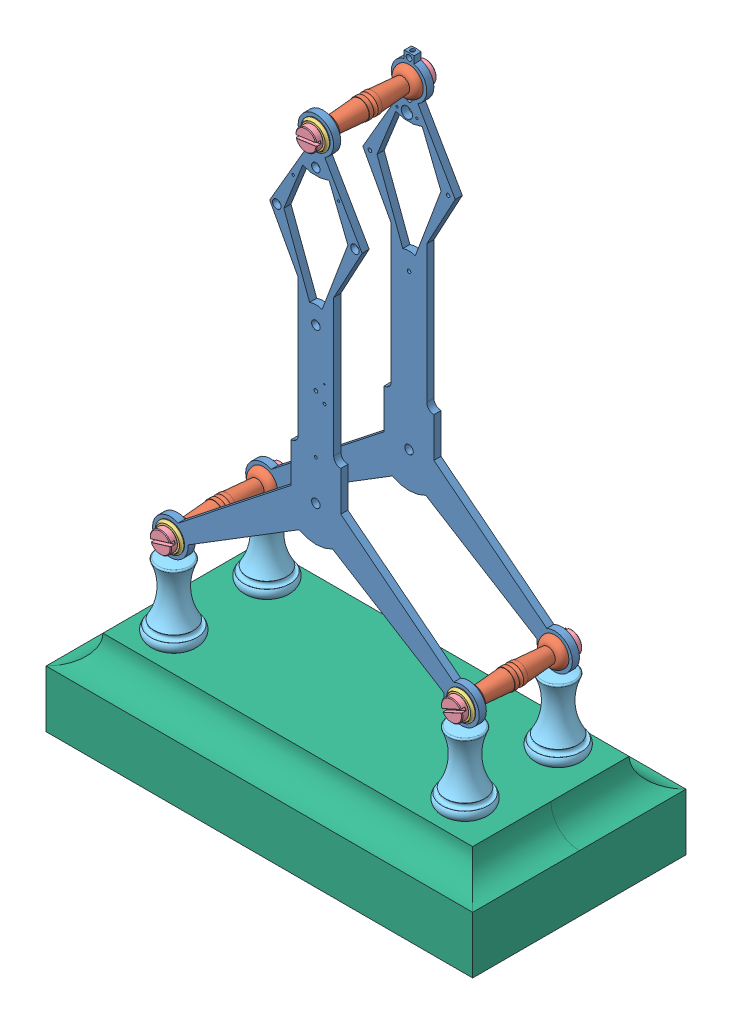
SolidWorks assembly frame assy, configuration Default. Lengths in mm.
Overall size (300 436.05 150).
22 component instances, 6 part files, 44 mates.
Components (placement in the parent):
- Frame-1: Frame [Front] at origin size (229.79 321.19 5)
- pillar-1: pillar [Default] at (0 115.9979 0) size (20 20 70.93)
- pillar-2: pillar [Default] at (102.394 -180.1971 0) x (0.987351 0.158553 0) z (0 0 1) size (20 20 70.93)
- pillar-3: pillar [Default] at (-102.394 -180.1971 0) x (0.959125 0.282984 0) z (0 0 1) size (20 20 70.93)
- Frame-2: Frame [Back] at (0 0 -60.5) x (-1 0 0) z (0 0 -1) size (229.79 326.05 5)
- washer-1: washer [Default] at (0 115.9979 7) x (0.258664 -0.965967 0) z (0 0 -1) size (20 20 2)
- frame screw-1: frame screw [Default] at (0 115.9979 7) x (-0.137342 0.990524 0) z (0.990524 0.137342 0) size (15 20 15)
- frame screw-2: frame screw [Default] at (-102.394 -180.1971 7) x (-0.292655 0.956218 0) z (0.956218 0.292655 0) size (15 20 15)
- washer-2: washer [Default] at (-102.394 -180.1971 7) x (0.408549 -0.912737 0) z (0 0 -1) size (20 20 2)
- frame screw-4: frame screw [Default] at (102.394 -180.1971 7) x (0.41203 -0.91117 0) z (-0.91117 -0.41203 0) size (15 20 15)
- washer-4: washer [Default] at (102.394 -180.1971 7) x (-0.521444 0.853286 0) z (0 0 -1) size (20 20 2)
- frame screw-6: frame screw [Default] at (102.394 -180.1971 -67.5) x (0.92649 0.37632 0) z (-0.37632 0.92649 0) size (15 20 15)
- washer-6: washer [Default] at (102.394 -180.1971 -67.5) x (-0.965884 -0.258974 0) z (0 0 1) size (20 20 2)
- frame screw-8: frame screw [Default] at (-102.394 -180.1971 -67.5) x (-0.887501 -0.460806 0) z (0.460806 -0.887501 0) size (15 20 15)
- washer-8: washer [Default] at (-102.394 -180.1971 -67.5) x (-0.90624 -0.422764 0) z (0 0 1) size (20 20 2)
- frame screw-10: frame screw [Default] at (0 115.9979 -67.5) x (0.741906 0.670504 0) z (-0.670504 0.741906 0) size (15 20 15)
- washer-10: washer [Default] at (0 115.9979 -67.5) x (-0.81906 -0.573708 0) z (0 0 1) size (20 20 2)
- foot-1: foot [Default] at (-102.394 -242.6971 2.5) x (0.145571 0 -0.989348) z (0.989348 0 0.145571) size (34 49.97 34)
- foot-2: foot [Default] at (102.394 -242.6971 2.5) x (-0.043484 0 -0.999054) z (0.999054 0 -0.043484) size (34 49.97 34)
- foot-3: foot [Default] at (102.394 -242.6971 -63) x (-0.257831 0 -0.96619) z (0.96619 0 -0.257831) size (34 49.97 34)
- foot-4: foot [Default] at (-102.394 -242.6971 -63) x (-0.477152 0 -0.878821) z (0.878821 0 -0.477152) size (34 49.97 34)
- base-1: base [Default] at (0 -302.6971 -30.25) size (300 60 150)
Mates (geometry in assembly coordinates):
- Coincident6: coincident: plane of Frame-1 through (0 0 0) normal (0 0 -1); plane of pillar-1 through (0 106.9979 0) normal (0 0 1)
- Concentric7: concentric: circle of Frame-1; circle of pillar-1
- Coincident8: coincident: plane of Frame-1 through (0 0 0) normal (0 0 -1); plane of pillar-2 through (103.821 -189.0832 0) normal (0 0 1)
- Concentric8: concentric: circle of Frame-1; circle of pillar-2
- Coincident9: coincident: plane of Frame-1 through (0 0 0) normal (0 0 -1); plane of pillar-3 through (-99.8472 -188.8292 0) normal (0 0 1)
- Concentric9: concentric: circle of Frame-1; circle of pillar-3
- Concentric17: concentric: cylinder of Frame-1 through (-102.394 -180.1971 5) axis (0 0 -1) radius 12.5; cylinder of Frame-2 through (-102.394 -180.1971 -65.5) axis (0 0 1) radius 12.5
- Coincident14: coincident: plane of Frame-1 through (0 0 5) normal (0 0 1); plane of washer-1 through (0 115.9979 5) normal (0 0 -1)
- Concentric18: concentric: circle of Frame-1; circle of washer-1
- Coincident13: coincident: plane of pillar-1 through (0 106.9979 -60.5) normal (0 0 -1); plane of Frame-2 through (0 0 -60.5) normal (0 0 1)
- Concentric16: concentric: circle of pillar-1; cylinder of Frame-2 through (0 115.9979 -198.0442) axis (0 0 1) radius 12.5
- Coincident15: coincident: plane of washer-1 through (0 115.9979 7) normal (0 0 1); plane of frame screw-1 through (0 115.9979 7) normal (0 0 -1)
- Concentric19: concentric: cylinder of washer-1 through (0 115.9979 5) axis (0 0 1) radius 3; cylinder of frame screw-1 through (0 115.9979 12) axis (0 0 -1) radius 7.5
- Coincident16: coincident: plane of frame screw-2 through (-102.394 -180.1971 7) normal (0 0 -1); plane of washer-2 through (-102.394 -180.1971 7) normal (0 0 1)
- Concentric20: concentric: cylinder of frame screw-2 through (-102.394 -180.1971 12) axis (0 0 -1) radius 7.5; cylinder of washer-2 through (-102.394 -180.1971 5) axis (0 0 1) radius 3
- Coincident17: coincident: plane of Frame-1 through (0 0 5) normal (0 0 1); plane of washer-2 through (-102.394 -180.1971 5) normal (0 0 -1)
- Concentric21: concentric: circle of Frame-1; circle of washer-2
- Coincident19: coincident: plane of frame screw-4 through (102.394 -180.1971 7) normal (0 0 -1); plane of washer-4 through (102.394 -180.1971 7) normal (0 0 1)
- Concentric23: concentric: cylinder of frame screw-4 through (102.394 -180.1971 12) axis (0 0 -1) radius 7.5; cylinder of washer-4 through (102.394 -180.1971 5) axis (0 0 1) radius 3
- Coincident20: coincident: plane of Frame-1 through (0 0 5) normal (0 0 1); plane of washer-4 through (102.394 -180.1971 5) normal (0 0 -1)
- Concentric24: concentric: circle of Frame-1; circle of washer-4
- Coincident22: coincident: plane of frame screw-6 through (102.394 -180.1971 -67.5) normal (0 0 1); plane of washer-6 through (102.394 -180.1971 -67.5) normal (0 0 -1)
- Concentric26: concentric: cylinder of frame screw-6 through (102.394 -180.1971 -72.5) axis (0 0 1) radius 7.5; cylinder of washer-6 through (102.394 -180.1971 -65.5) axis (0 0 -1) radius 3
- Coincident23: coincident: plane of Frame-2 through (0 0 -65.5) normal (0 0 -1); plane of washer-6 through (102.394 -180.1971 -65.5) normal (0 0 1)
- Concentric27: concentric: circle of Frame-2; circle of washer-6
- Coincident25: coincident: plane of frame screw-8 through (-102.394 -180.1971 -67.5) normal (0 0 1); plane of washer-8 through (-102.394 -180.1971 -67.5) normal (0 0 -1)
- Concentric29: concentric: cylinder of frame screw-8 through (-102.394 -180.1971 -72.5) axis (0 0 1) radius 7.5; cylinder of washer-8 through (-102.394 -180.1971 -65.5) axis (0 0 -1) radius 3
- Coincident26: coincident: plane of Frame-2 through (0 0 -65.5) normal (0 0 -1); plane of washer-8 through (-102.394 -180.1971 -65.5) normal (0 0 1)
- Concentric30: concentric: circle of Frame-2; circle of washer-8
- Coincident28: coincident: plane of frame screw-10 through (0 115.9979 -67.5) normal (0 0 1); plane of washer-10 through (0 115.9979 -67.5) normal (0 0 -1)
- Concentric32: concentric: cylinder of frame screw-10 through (0 115.9979 -72.5) axis (0 0 1) radius 7.5; cylinder of washer-10 through (0 115.9979 -65.5) axis (0 0 -1) radius 3
- Coincident29: coincident: plane of Frame-2 through (0 0 -65.5) normal (0 0 -1); plane of washer-10 through (0 115.9979 -65.5) normal (0 0 1)
- Concentric33: concentric: circle of Frame-2; circle of washer-10
- Concentric35: concentric: cylinder of Frame-1 through (-102.394 -192.6971 2.5) axis (0 -1 0) radius 1.65; cylinder of foot-1 through (-102.394 -192.6971 2.5) axis (0 -1 0) radius 2
- Coincident31: coincident: plane of Frame-1 through (0 -192.6971 0) normal (0 1 0); plane of foot-1 through (-102.394 -192.6971 2.5) normal (0 1 0)
- Coincident32: coincident: plane of Frame-1 through (0 -192.6971 0) normal (0 1 0); plane of foot-2 through (102.394 -192.6971 2.5) normal (0 1 0)
- Concentric36: concentric: cylinder of Frame-1 through (102.394 -192.6971 2.5) axis (0 -1 0) radius 1.65; cylinder of foot-2 through (102.394 -192.6971 2.5) axis (0 -1 0) radius 2
- Coincident33: coincident: plane of Frame-1 through (0 -192.6971 0) normal (0 1 0); plane of foot-3 through (102.394 -192.6971 -63) normal (0 1 0)
- Concentric37: concentric: cylinder of Frame-2 through (102.394 -192.6971 -63) axis (0 -1 0) radius 1.65; cylinder of foot-3 through (102.394 -192.6971 -63) axis (0 -1 0) radius 2
- Coincident34: coincident: plane of Frame-1 through (0 -192.6971 0) normal (0 1 0); plane of foot-4 through (-102.394 -192.6971 -63) normal (0 1 0)
- Concentric38: concentric: cylinder of Frame-2 through (-102.394 -192.6971 -63) axis (0 -1 0) radius 1.65; cylinder of foot-4 through (-102.394 -192.6971 -63) axis (0 -1 0) radius 2
- Coincident36: coincident: plane of foot-1 through (-102.394 -242.6971 2.5) normal (0 1 0); plane of base-1 through (0 -242.6971 -30.25) normal (0 1 0)
- Width1: width: plane of base-1 through (150 -242.6971 44.75) normal (0 0 1); plane of base-1 through (150 -242.6971 -105.25) normal (0 0 -1); plane of Frame-2 through (0 0 -65.5) normal (0 0 -1); plane of Frame-1 through (0 0 5) normal (0 0 1)
- Width2: width: plane of base-1 through (150 -242.6971 -105.25) normal (1 0 0); plane of base-1 through (-150 -242.6971 -105.25) normal (-1 0 0); plane of Frame-1 through (-12.5 0 5) normal (-1 0 0); plane of Frame-1 through (12.5 0 5) normal (1 0 0)
